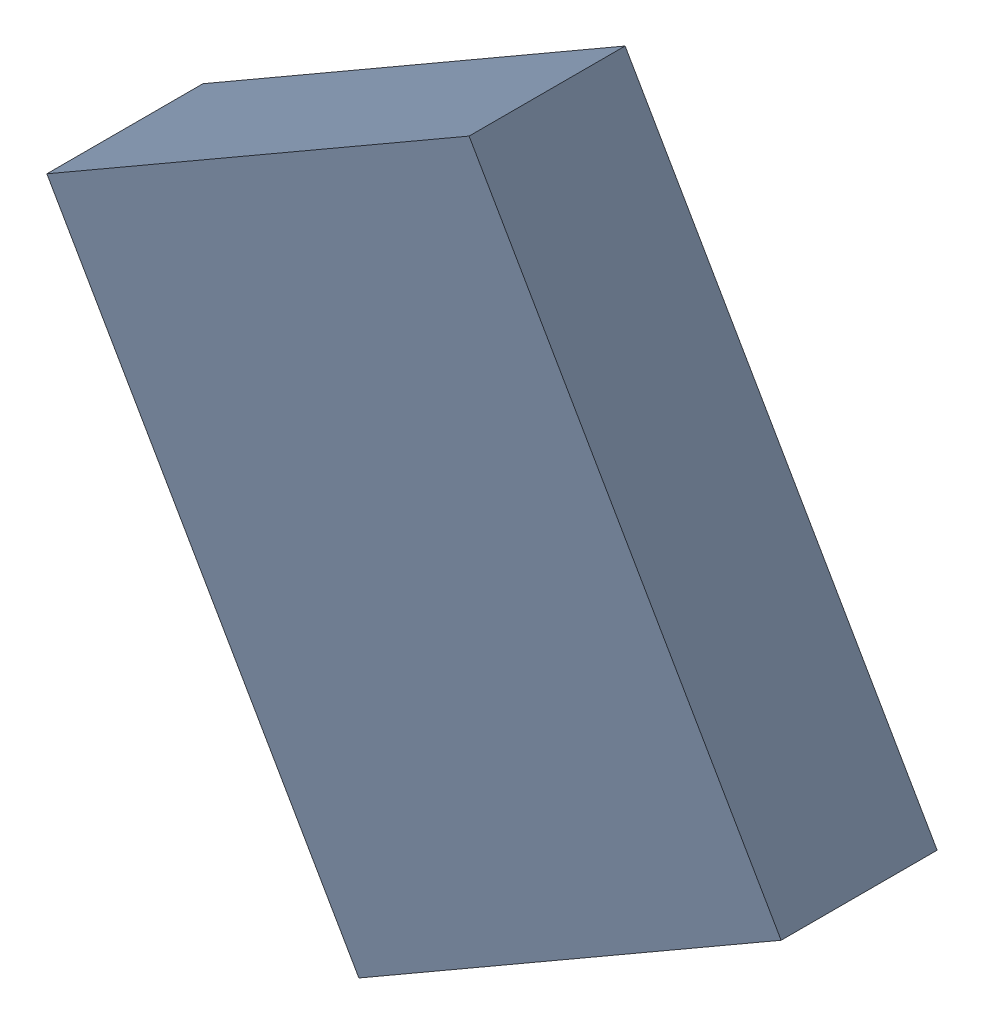
SolidWorks assembly X_TDA_TDA5, configuration Standard. Lengths in mm.
Overall size (3.77 4.02 0.8).
2 component instances, 1 part files, 0 mates.
Components (placement in the parent):
- 885545640-1: 885545640 [Standard] at (-34.8042 -23.4933 0) size (3.77 4.02 0.8)
  - Extruded_2-1: Extruded_2 [Standard] at origin size (3.77 4.02 0.8)
